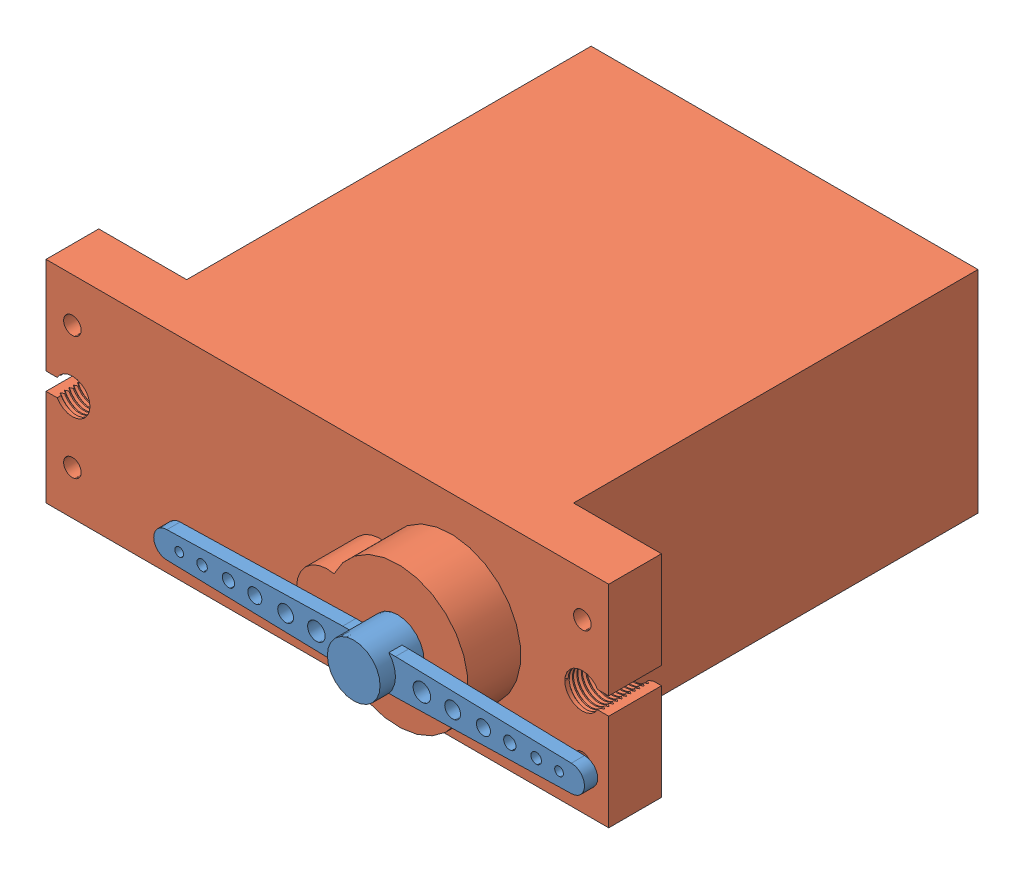
SolidWorks assembly servo_assem, configuration Default. Lengths in mm.
Overall size (35.25 12 31.5).
2 component instances, 2 part files, 4 mates.
Components (placement in the parent):
- servo_blade-1: servo_blade [Default] at (-41.7985 6 21.3956) size (24.5 3 2.5)
- servo_body-1: servo_body [Default] at (-59.7985 6 3.8956) x (0 0 -1) z (1 0 0) size (31 12 32)
Mates (geometry in assembly coordinates):
- Coincident1: coincident anti-aligned: plane of servo_body-1 through (-37.7985 0 15.3956) normal (0 -1 0)
- Parallel1: parallel aligned: plane of servo_body-1 through (-59.7985 6 18.3956) normal (0 0 1)
- Coincident3: coincident anti-aligned: plane of servo_blade-1 through (-41.7985 6 23.3956) normal (0 0 -1); plane of servo_body-1 through (-41.7985 6 23.3956) normal (0 0 1)
- Concentric1: concentric aligned: cylinder of servo_blade-1 through (-41.7985 6 23.3956) axis (0 0 -1) radius 1; cylinder of servo_body-1 through (-41.7985 6 23.3956) axis (0 0 -1) radius 1
